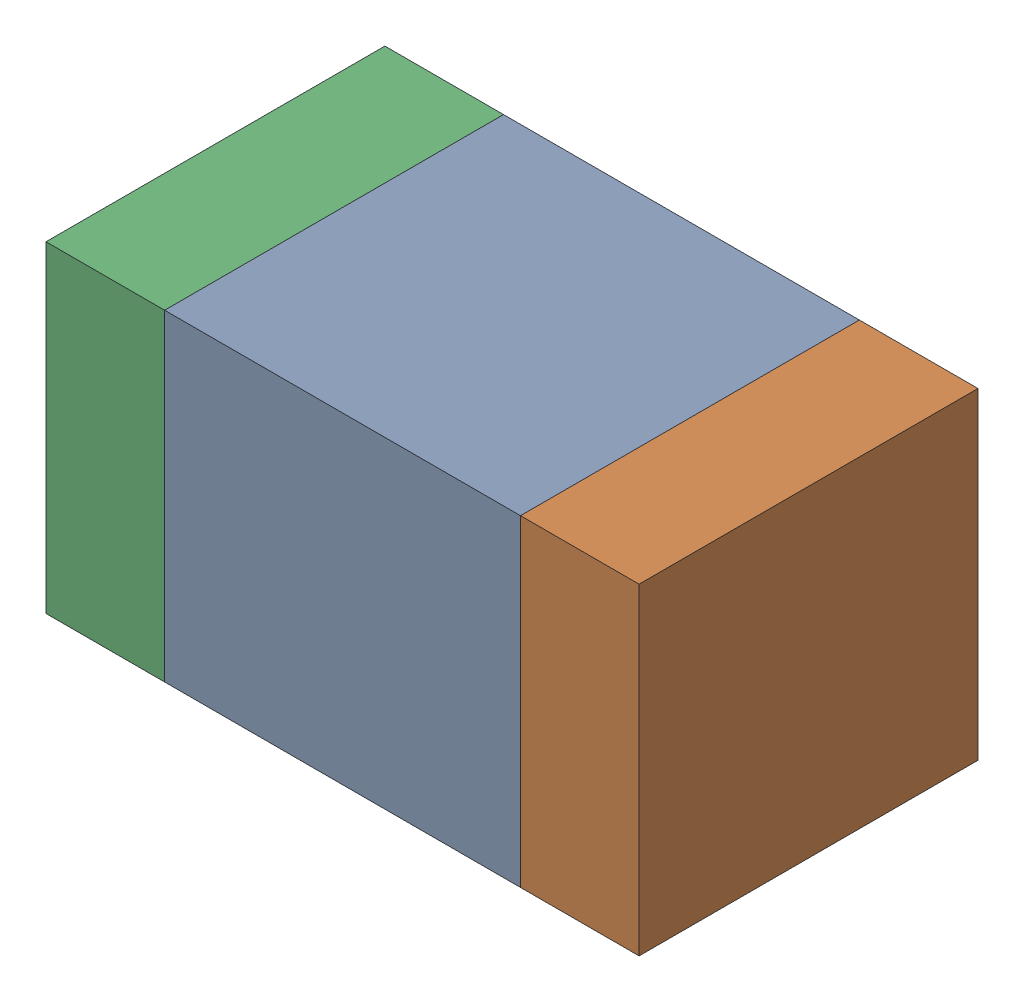
SolidWorks assembly C6-2, configuration Default. Lengths in mm.
Overall size (1.75 0.95 1).
6 component instances, 2 part files, 0 mates.
Components (placement in the parent):
- 959208800-2-1: 959208800-2 [Default] at (135.5285 81.379 0) size (1.05 0.95 1)
  - Extruded-79-1: Extruded-79 [Default] at origin size (1.05 0.95 1)
- 959208936-2-1: 959208936-2 [Default] at (136.2285 81.379 0) size (0.35 0.95 1)
  - Extruded-78-1: Extruded-78 [Default] at origin size (0.35 0.95 1)
- 959208936-2-2: 959208936-2 [Default] at (134.8286 81.379 0) size (0.35 0.95 1)
  - Extruded-78-1: Extruded-78 [Default] at origin size (0.35 0.95 1)
